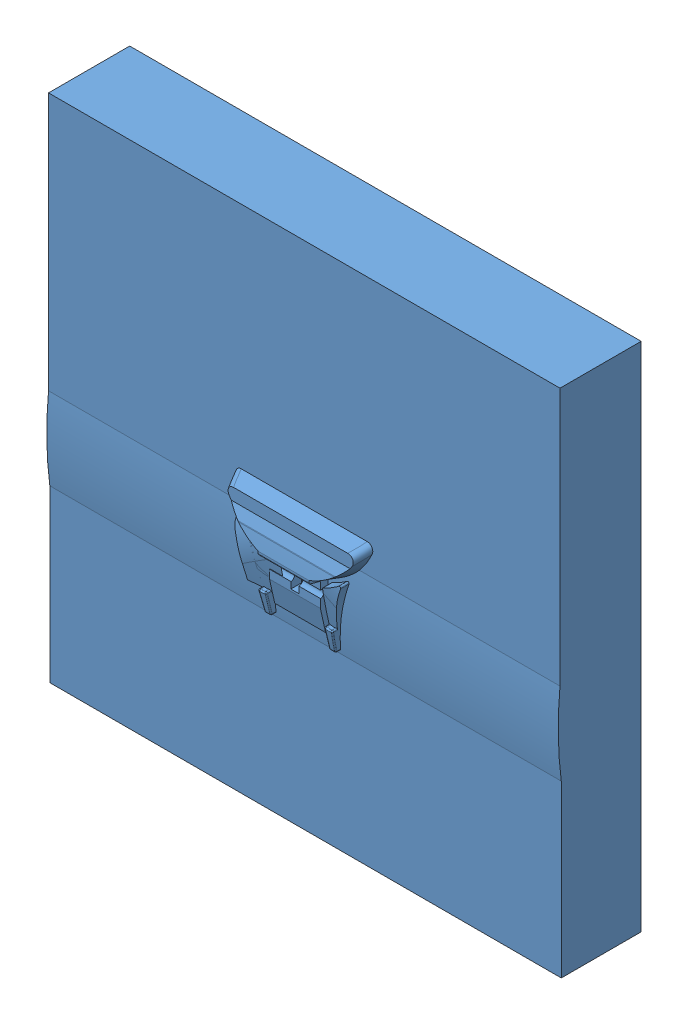
SolidWorks assembly SB_ H 304, configuration Default. Lengths in mm.
Overall size (63 63 12.75).
6 component instances, 6 part files, 24 mates.
Components (placement in the parent):
- T_004_03-1: T_004_03 [По умолчанию] at (-0.05 0 0.0167) size (15.52 11.48 4.35) (hidden)
- Lit_304-2: Lit_304 [По умолчанию] at (0 -0.4114 0.0095) size (9.46 21.26 1.8) (hidden)
- Elek_H304-1: Elek_H304 [По умолчанию] at origin size (63 63 13.22) (hidden)
- Matrica_H304-1: Matrica_H304 [По умолчанию] at (0 0 -9.8397) x (-1 0 0) z (0 0 -1) size (63 63 11.13) (hidden)
- Puanson_H304-1: Puanson_H304 [По умолчанию] at (0 0 10.1603) size (63 63 12.75)
- Pro_H304-1: Pro_H304 [По умолчанию] at (0 0 -9.8397) x (-1 0 0) z (0 0 -1) (suppressed, hidden)
Mates (geometry in assembly coordinates):
- Совпадение1: coincident aligned: plane of T_004_03-1 through (0 0 0.0167) normal (1 0 0); plane of assembly
- Параллельность1: parallel aligned: plane of T_004_03-1 through (-0.05 0 0.0167) normal (0 0 1); plane of assembly
- Совпадение6: coincident: point of T_004_03-1; plane of assembly
- Совпадение7: coincident: point of T_004_03-1; plane of assembly
- Совпадение8: coincident aligned: plane of T_004_03-1 through (-0.05 0 0.0167) normal (0 1 0); plane of assembly
- Совпадение11: coincident anti-aligned: plane of Lit_304-2 through (-0.0007 -6.8011 0) normal (0 0 -1); plane of assembly
- Совпадение12: coincident aligned: plane of Lit_304-2 through (0 -0.4114 0.0095) normal (1 0 0); plane of assembly
- Совпадение13: coincident anti-aligned: line of T_004_03-1 through (-4.8236 -4.3013 0) axis (1 0 0); line of Lit_304-2 through (4.4642 -4.3013 0) axis (-1 0 0)
- На месте1: in place: plane of assembly; plane of Elek_H304-1; moOrthogonalPlaneRef_w of assembly; plane of ?; moOrthogonalPlaneRef_w of assembly; plane of ?
- Совпадение14: coincident aligned: plane of ?; plane of assembly
- Совпадение15: coincident aligned: plane of Elek_H304-1 through (0 0 0) normal (0 1 0); moOrthogonalPlaneRef_w of assembly
- Совпадение16: coincident anti-aligned: plane of Elek_H304-1 through (0 0 0) normal (1 0 0); moOrthogonalPlaneRef_w of assembly
- На месте2: in place: plane of Elek_H304-1 through (31.5 37.6989 -9.8397) normal (0 0 -1); unknown of ?
- Совпадение17: coincident aligned: plane of ?; plane of ?
- Совпадение18: coincident aligned: moOrthogonalPlaneRef_w of Elek_H304-1 through (0 0 -9.8397) axis (0 1 0); plane of ?
- Совпадение19: coincident anti-aligned: moOrthogonalPlaneRef_w of Elek_H304-1 through (0 0 -9.8397) axis (1 0 0); plane of ? through (0 0 -9.8397) normal (-1 0 0)
- На месте3: in place: plane of ? through (31.5 -25.3011 10.1603) normal (0 0 1); unknown of Puanson_H304-1
- Совпадение20: coincident aligned: plane of ?; plane of ?
- Совпадение21: coincident aligned: moOrthogonalPlaneRef_w of ? through (0 0 10.1603) axis (0 1 0); plane of Puanson_H304-1 through (0 0 10.1603) normal (0 1 0)
- Совпадение22: coincident anti-aligned: moOrthogonalPlaneRef_w of ? through (0 0 10.1603) axis (-1 0 0); plane of Puanson_H304-1 through (0 0 10.1603) normal (1 0 0)
- На месте4: in place: plane of Puanson_H304-1; plane of ?; moOrthogonalPlaneRef_w of ?; plane of ?; moOrthogonalPlaneRef_w of ?; plane of ?
- Совпадение23: coincident aligned: plane of ?; plane of ?
- Совпадение24: coincident aligned: moOrthogonalPlaneRef_w of ?; plane of ?
- Совпадение25: coincident anti-aligned: moOrthogonalPlaneRef_w of Elek_H304-1; plane of Elek_H304-1
